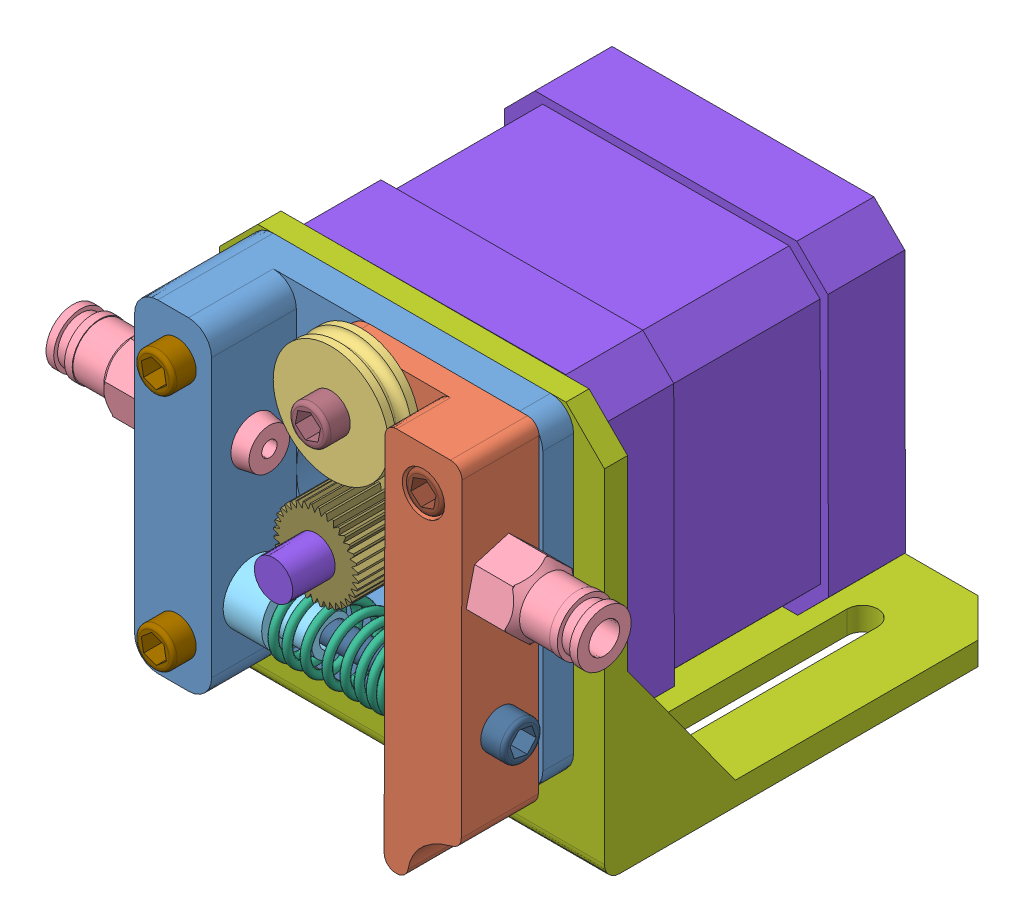
SolidWorks assembly Bowden Assembly, configuration Default. Lengths in mm.
Overall size (68.49 53.54 71.5).
16 component instances, 14 part files, 36 mates.
Components (placement in the parent):
- Main Block-1: Main Block [Default] at (16.5906 16.7583 27.7621) size (42 42 15)
- Arm-1: Arm [Default] at (32.0447 12.7584 31.7621) x (0.999997 -0.002353 0) z (0 0 1) size (25 50 10)
- Feed Bearing-1: Feed Bearing [Default] at (17.0906 32.2936 34.7621) size (15 15 4)
- PTFE 4mm Fitting-1: PTFE 4mm Fitting [Default] at (7.5906 22.7583 37.2621) x (0 0 1) z (-1 0 0) size (9.52 9.62 25.5)
- PTFE 4mm Fitting-2: PTFE 4mm Fitting [Default] at (25.0683 22.7748 36.7621) x (0 0 -1) z (0.999997 -0.002353 0) size (9.52 9.62 25.5)
- Adjust Mount-1: Adjust Mount [Default] at (5.5906 5.7583 37.2621) x (0 0 -1) z (1 0 0) size (8 8 10)
- Compression Spring-1: Compression Spring [Default] at (26.6918 6.1319 36.8921) x (-0.03687 0.954593 -0.295622) z (-0.999309 -0.03662 0.006384) size (9 9 16.75)
- Bowden LBracket-1: Bowden LBracket [Default] at (16.5906 -13.7417 1.0121) x (0 0 -1) z (0 1 0) size (53.5 50 51.5)
- Bowben Nema 17-1: Bowben Nema 17 [Default] at (16.6316 16.7994 -15.2379) x (0.999996 0.002653 0) z (0 0 1) size (42 42 61)
- Hex M3x22-5: Hex M3x22 [Default] at (1.0906 1.2583 45.7621) x (0.230478 -0.973077 0) z (0 0 -1) size (5 5 25)
- Hex M3x22-7: Hex M3x22 [Default] at (1.0906 32.2583 45.7621) x (0.230478 -0.973077 0) z (0 0 -1) size (5 5 25)
- Hex M3x25-1: Hex M3x25 [Default] at (40.0282 5.7396 36.7621) x (0.002187 0.92966 0.368411) z (-0.999997 0.002353 0) size (5 5 28)
- Hex M3x20-3: Hex M3x20 [Default] at (32.0906 32.2583 41.7621) x (-0.923728 -0.383049 0) z (0 0 -1) size (5 5 23)
- Toothed Filament Feed-1: Toothed Filament Feed [Default] at (16.6316 16.7994 40.2533) x (-0.928407 -0.371565 0) z (0 0 -1) size (10.98 10.98 11)
- Hex M3x6-1: Hex M3x6 [Default] at (17.0906 32.2936 41.7621) x (-0.923728 -0.383049 0) z (0 0 -1) size (5 5 9)
- Hex M3x15-1: Hex M3x15 [Default] at (-7.4094 5.7583 37.2621) x (0 -0.924225 -0.381849) z (1 0 0) size (5 5 18)
Mates (geometry in assembly coordinates):
- Concentric1: concentric aligned: cylinder of Main Block-1 through (32.0906 32.2583 21.7621) axis (0 0 1) radius 1.75; cylinder of Arm-1 through (32.0906 32.2583 31.7621) axis (0 0 1) radius 1.75
- Coincident1: coincident anti-aligned: plane of Main Block-1 through (16.5906 16.7583 31.7621) normal (0 0 1); plane of Arm-1 through (32.0447 12.7584 31.7621) normal (0 0 -1)
- Concentric2: concentric aligned: cylinder of Arm-1 through (17.0906 32.2936 19.7621) axis (0 0 1) radius 1.35; cylinder of Feed Bearing-1 through (17.0906 32.2936 33.7621) axis (0 0 1) radius 1.5
- Coincident2: coincident anti-aligned: plane of Arm-1 through (12.1036 37.8054 34.7621) normal (0 0 1); plane of Feed Bearing-1 through (17.0906 32.2936 34.7621) normal (0 0 -1)
- Concentric3: concentric anti-aligned: cylinder of Main Block-1 through (16.5906 22.7583 37.2621) axis (-1 0 0) radius 3; cylinder of PTFE 4mm Fitting-1 through (-4.4094 22.7583 37.2621) axis (1 0 0) radius 3
- Coincident3: coincident anti-aligned: plane of Main Block-1 through (-4.4094 37.7583 31.7621) normal (-1 0 0); plane of PTFE 4mm Fitting-1 through (-4.4094 22.7583 37.2621) normal (1 0 0)
- Concentric4: concentric anti-aligned: cylinder of Arm-1 through (24.0683 22.7772 36.7621) axis (0.999997 -0.002353 0) radius 3; cylinder of PTFE 4mm Fitting-2 through (37.0682 22.7466 36.7621) axis (-0.999997 0.002353 0) radius 3
- Coincident4: coincident anti-aligned: plane of Arm-1 through (37.1035 37.7465 41.7621) normal (0.999997 -0.002353 0); plane of PTFE 4mm Fitting-2 through (37.0682 22.7466 36.7621) normal (-0.999997 0.002353 0)
- Coincident5: coincident anti-aligned: plane of Main Block-1 through (5.5906 37.7583 42.7621) normal (1 0 0); plane of Adjust Mount-1 through (5.5906 5.7583 37.2621) normal (-1 0 0)
- Coincident6: coincident anti-aligned: plane of Main Block-1 through (5.5906 37.7583 42.7621) normal (1 0 0); plane of Adjust Mount-1 through (5.5906 5.7583 37.2621) normal (-1 0 0)
- Concentric5: concentric aligned: cylinder of Main Block-1 through (16.5906 5.7583 37.2621) axis (-1 0 0) radius 1.5; cylinder of Adjust Mount-1 through (15.5906 5.7583 37.2621) axis (-1 0 0) radius 1.5
- Coincident7: coincident anti-aligned: plane of Main Block-1 through (16.5906 16.7583 27.7621) normal (0 0 -1); plane of Bowden LBracket-1 through (-8.4094 37.7583 27.7621) normal (0 0 1)
- Concentric6: concentric aligned: cylinder of Main Block-1 through (1.0906 32.2583 21.7621) axis (0 0 1) radius 1.75; cylinder of Bowden LBracket-1 through (1.0906 32.2583 17.7621) axis (0 0 1) radius 1.75
- Concentric7: concentric aligned: cylinder of Main Block-1 through (32.0906 32.2583 21.7621) axis (0 0 1) radius 1.75; cylinder of Bowden LBracket-1 through (32.0906 32.2583 17.7621) axis (0 0 1) radius 1.75
- Concentric8: concentric aligned: cylinder of Bowden LBracket-1 through (1.0906 32.2583 17.7621) axis (0 0 1) radius 1.75; cylinder of Bowben Nema 17-1 through (1.0905 32.2582 -15.2379) axis (0 0 1) radius 1.5
- Concentric9: concentric aligned: cylinder of Bowden LBracket-1 through (32.0906 32.2583 17.7621) axis (0 0 1) radius 1.75; cylinder of Bowben Nema 17-1 through (32.0906 32.2583 -15.2379) axis (0 0 1) radius 1.5
- Coincident8: coincident anti-aligned: plane of Bowden LBracket-1 through (-8.4094 -10.7417 24.7621) normal (0 0 -1); plane of Bowben Nema 17-1 through (16.6316 16.7994 24.7621) normal (0 0 1)
- Coincident9: coincident anti-aligned: plane of Main Block-1 through (16.5906 16.7583 42.7621) normal (0 0 1); plane of ? through (1.0906 32.2583 42.7621) normal (0 0 -1)
- Concentric10: concentric aligned: cylinder of Main Block-1 through (1.0906 32.2583 21.7621) axis (0 0 1) radius 1.75; cylinder of ? through (1.0906 32.2583 20.7621) axis (0 0 1) radius 1.5
- Coincident10: coincident anti-aligned: plane of Main Block-1 through (16.5906 16.7583 42.7621) normal (0 0 1); plane of Hex M3x22-5 through (1.0906 1.2583 42.7621) normal (0 0 -1)
- Concentric11: concentric aligned: cylinder of Main Block-1 through (1.0906 1.2583 21.7621) axis (0 0 1) radius 1.75; cylinder of Hex M3x22-5 through (1.0906 1.2583 20.7621) axis (0 0 1) radius 1.5
- Concentric12: concentric aligned: cylinder of Main Block-1 through (1.0906 32.2583 21.7621) axis (0 0 1) radius 1.75; cylinder of Hex M3x22-7 through (1.0906 32.2583 20.7621) axis (0 0 1) radius 1.5
- Coincident11: coincident anti-aligned: plane of Main Block-1 through (16.5906 16.7583 42.7621) normal (0 0 1); plane of Hex M3x22-7 through (1.0906 32.2583 42.7621) normal (0 0 -1)
- Coincident12: coincident anti-aligned: plane of Arm-1 through (32.0906 32.2583 38.7621) normal (0 0 1); plane of Hex M3x20-3 through (32.0906 32.2583 38.7621) normal (0 0 -1)
- Concentric13: concentric aligned: cylinder of Arm-1 through (32.0906 32.2583 31.7621) axis (0 0 1) radius 1.75; cylinder of Hex M3x20-3 through (32.0906 32.2583 13.7621) axis (0 0 1) radius 1.5
- Concentric14: concentric: cylinder of Arm-1 through (22.0223 5.7842 36.7621) axis (0.999997 -0.002579 0) radius 1.5; cylinder of ? through (17.0223 5.7971 36.7621) axis (0.999997 -0.002579 0) radius 1.5
- Coincident13: coincident anti-aligned: plane of Arm-1; plane of ? through (37.0222 5.7455 36.7621) normal (-0.999997 0.002579 0)
- Concentric15: concentric aligned: cylinder of Arm-1 through (22.0283 5.7819 36.7621) axis (0.999997 -0.002353 0) radius 1.5; cylinder of Hex M3x25-1 through (12.0283 5.8054 36.7621) axis (0.999997 -0.002353 0) radius 1.5
- Coincident14: coincident anti-aligned: plane of Arm-1 through (37.1035 37.7465 41.7621) normal (0.999997 -0.002353 0); plane of Hex M3x25-1 through (37.0282 5.7466 36.7621) normal (-0.999997 0.002353 0)
- Coincident15: coincident anti-aligned: plane of Arm-1 through (32.0906 32.2583 38.7621) normal (0 0 1); plane of Hex M3x20-3 through (32.0906 32.2583 38.7621) normal (0 0 -1)
- Concentric16: concentric aligned: cylinder of Arm-1 through (32.0906 32.2583 31.7621) axis (0 0 1) radius 1.75; cylinder of Hex M3x20-3 through (32.0906 32.2583 18.7621) axis (0 0 1) radius 1.5
- Concentric17: concentric aligned: cylinder of Bowben Nema 17-1 through (16.6316 16.7994 45.7621) axis (0 0 -1) radius 2.5; cylinder of Toothed Filament Feed-1 through (16.6316 16.7994 41.2533) axis (0 0 -1) radius 2.5
- Concentric18: concentric aligned: cylinder of Feed Bearing-1 through (17.0906 32.2936 33.7621) axis (0 0 1) radius 1.5; cylinder of Hex M3x6-1 through (17.0906 32.2936 32.7621) axis (0 0 1) radius 1.5
- Coincident16: coincident anti-aligned: plane of Feed Bearing-1 through (17.0906 32.2936 38.7621) normal (0 0 1); plane of Hex M3x6-1 through (17.0906 32.2936 38.7621) normal (0 0 -1)
- Concentric19: concentric aligned: cylinder of Main Block-1 through (16.5906 5.7583 37.2621) axis (-1 0 0) radius 1.5; cylinder of Hex M3x15-1 through (10.5906 5.7583 37.2621) axis (-1 0 0) radius 1.5
- Coincident17: coincident anti-aligned: plane of Main Block-1 through (-4.4094 37.7583 31.7621) normal (-1 0 0); plane of Hex M3x15-1 through (-4.4094 5.7583 37.2621) normal (1 0 0)
